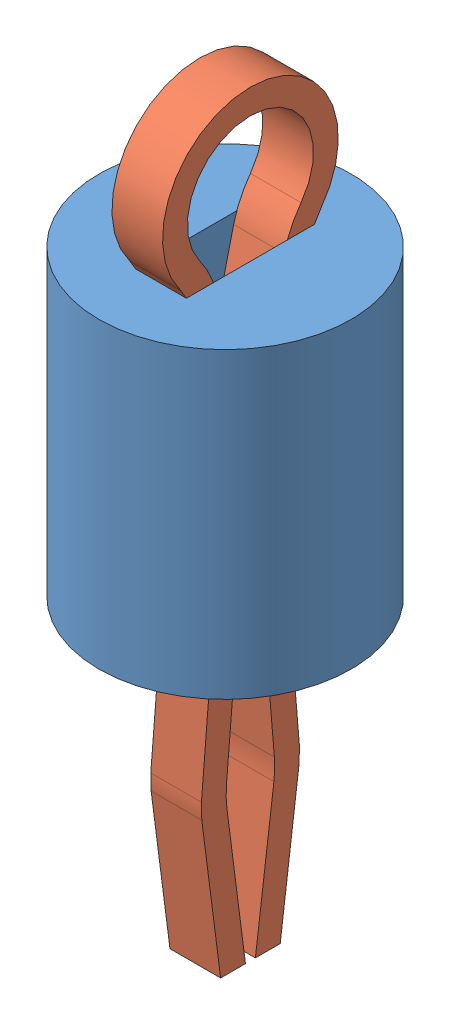
SolidWorks assembly 5119, configuration Default. Lengths in mm.
Overall size (2.54 7.62 2.54).
2 component instances, 2 part files, 6 mates.
Components (placement in the parent):
- Spacer-purple-1: Spacer-purple [Default] x (0 0 1) z (0 1 0) size (2.54 2.54 3.05)
- Contact-1: Contact [Default] x (0 0 -1) z (0 1 0) size (1.77 0.51 7.62)
Mates (geometry in assembly coordinates):
- Coincident1: coincident aligned: plane of Spacer-purple-1 through (0 0 0) normal (1 0 0)
- Coincident2: coincident aligned: plane of Spacer-purple-1 through (0 0 0) normal (0 0 1)
- Coincident3: coincident anti-aligned: plane of Spacer-purple-1 through (0 0 0) normal (0 -1 0)
- Coincident4: coincident anti-aligned: plane of Contact-1 through (0 0 0) normal (-1 0 0)
- Coincident5: coincident anti-aligned: plane of Contact-1 through (0 0 0) normal (0 0 -1)
- Distance1: distance = 3.05 mm aligned: plane of Spacer-purple-1 through (0 0 0) normal (0 -1 0); plane of Contact-1 through (0 -3.05 -0.175) normal (0 -1 0)
